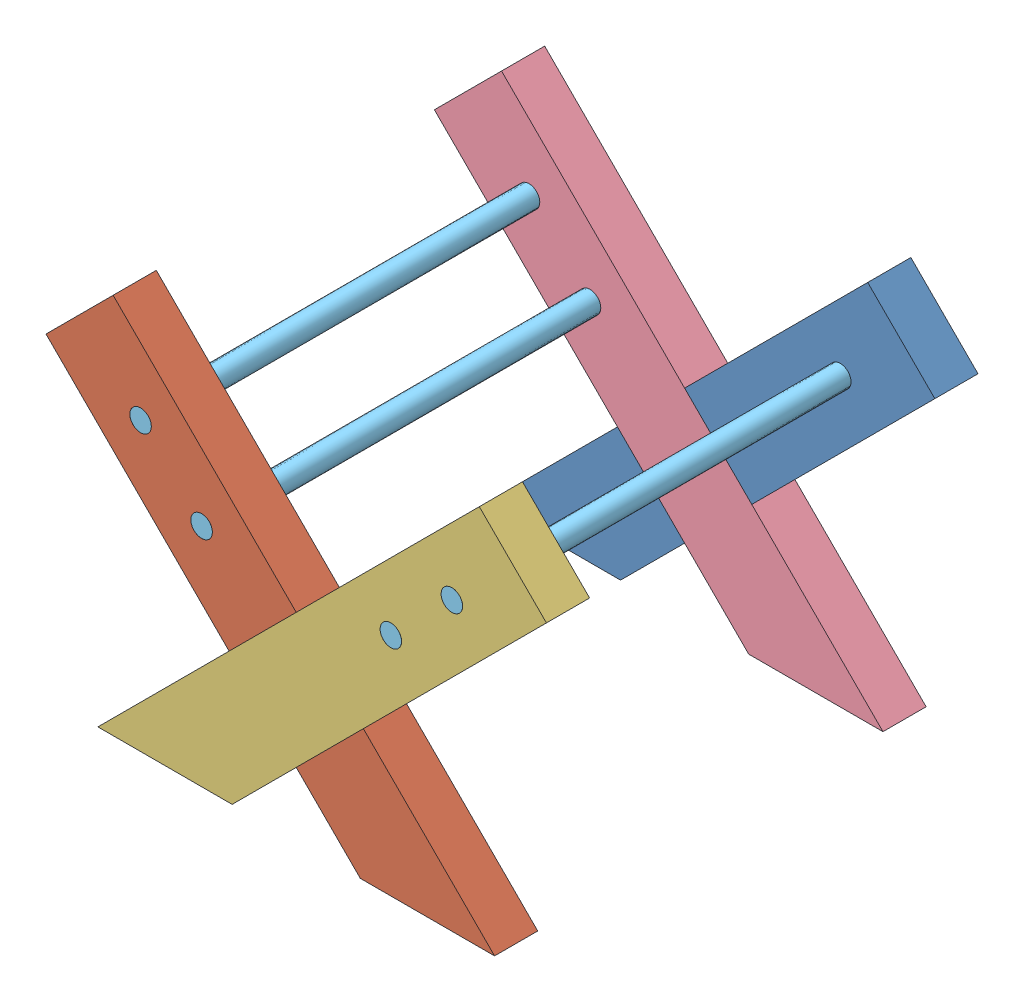
SolidWorks assembly ASSEM2, configuration Default. Lengths in mm.
Overall size (231.93 176.78 200).
9 component instances, 6 part files, 19 mates.
Components (placement in the parent):
- PART1 SIDE-1: PART1 SIDE [Default] at (-150.5114 -91.6596 10) size (207.89 176.78 20)
- PART1 SIDE 135-1: PART1 SIDE 135 [Default] at (-28.889 -91.6596 190) size (207.89 176.78 20)
- PART2 SIDE-1: PART2 SIDE [Default] at (-150.5114 -91.6596 190) size (207.89 176.78 20)
- PART2 SIDE 135-1: PART2 SIDE 135 [Default] at (-28.889 -91.6596 10) size (207.89 176.78 20)
- DOWEL-1: DOWEL [Default] at (13.5374 41.2765 -10) x (0.943711 -0.330771 0) z (0 0 1) size (10 10 200)
- DOWEL-2: DOWEL [Default] at (-14.7469 12.9922 -10) x (0.892618 0.450814 0) z (0 0 1) size (10 10 200)
- DOWEL-3: DOWEL [Default] at (-102.4281 12.9922 -10) x (0.859158 -0.51171 0) z (0 0 1) size (10 10 200)
- DOWEL-4: DOWEL [Default] at (-130.7124 41.2765 -10) x (0.836028 0.548687 0) z (0 0 1) size (10 10 200)
- CD-1: CD [Default] at (-138.4905 80.1674 74.2612) x (0.707107 -0.707107 0) z (0 0 1) size (130 120 15) (hidden)
Mates (geometry in assembly coordinates):
- Coincident1: coincident: point of PART1 SIDE 135-1; point of PART2 SIDE-1
- Coincident2: coincident: point of PART1 SIDE-1; point of PART2 SIDE 135-1
- Coincident4: coincident aligned: circle of PART1 SIDE-1; circle of DOWEL-1
- Concentric2: concentric aligned: circle of PART2 SIDE-1; circle of DOWEL-1
- Coincident9: coincident: point of PART1 SIDE 135-1; point of PART2 SIDE-1
- Concentric3: concentric aligned: circle of PART2 SIDE-1; circle of DOWEL-2
- Coincident11: coincident aligned: circle of PART1 SIDE-1; circle of DOWEL-2
- Coincident12: coincident aligned: plane of PART2 SIDE-1 through (-88.286 -91.6596 190) normal (0 0 1); plane of DOWEL-1 through (13.5374 41.2765 190) normal (0 0 1)
- Coincident13: coincident: point of PART1 SIDE-1; point of PART2 SIDE 135-1
- Coincident16: coincident aligned: plane of PART1 SIDE-1 through (-88.286 -91.6596 10) normal (0 0 1); plane of PART2 SIDE 135-1 through (-28.889 -91.6596 10) normal (0 0 1)
- Coincident17: coincident aligned: plane of PART1 SIDE 135-1 through (-320.217 -91.6596 190) normal (0 0 1); plane of PART2 SIDE-1 through (-88.286 -91.6596 190) normal (0 0 1)
- Coincident18: coincident aligned: circle of PART1 SIDE 135-1; circle of DOWEL-3
- Coincident19: coincident aligned: plane of PART2 SIDE 135-1 through (-28.889 -91.6596 -10) normal (0 0 -1); plane of DOWEL-3 through (-102.4281 12.9922 -10) normal (0 0 -1)
- Coincident22: coincident aligned: plane of PART1 SIDE 135-1 through (-320.217 -91.6596 190) normal (0 0 1); circle of DOWEL-4
- Coincident23: coincident aligned: plane of PART2 SIDE 135-1 through (-28.889 -91.6596 -10) normal (0 0 -1); plane of DOWEL-4 through (-130.7124 41.2765 -10) normal (0 0 -1)
- Coincident24: coincident anti-aligned: plane of PART2 SIDE 135-1 through (-28.889 -91.6596 -10) normal (0 0 -1); circle of DOWEL-4
- Coincident25: coincident aligned: circle of PART1 SIDE 135-1; circle of DOWEL-4
- Tangent1: tangent anti-aligned: cylinder of DOWEL-2 through (-14.7469 12.9922 190) axis (0 0 -1) radius 5; plane of CD-1 through (-46.5667 -11.7565 89.2612) normal (0.707107 -0.707107 0)
- Coincident26: coincident anti-aligned: plane of PART2 SIDE 135-1 through (-143.4403 85.1171 -10) normal (0.707107 0.707107 0); plane of CD-1 through (-138.4905 80.1674 89.2612) normal (-0.707107 -0.707107 0)
